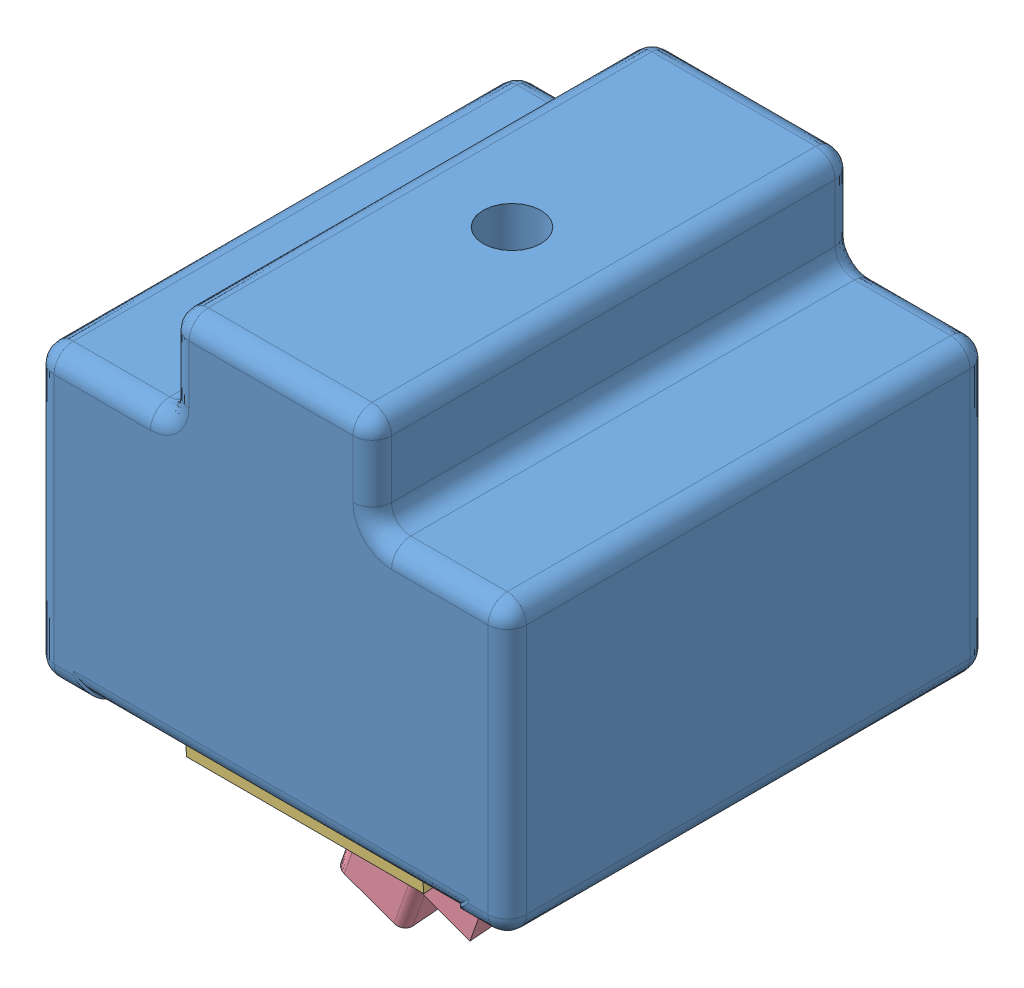
SolidWorks assembly Ankle Assembled, configuration Exploded. Lengths in mm.
Overall size (62.23 81.72 63.5).
6 component instances, 6 part files, 16 mates.
Components (placement in the parent):
- Ankle Exterior-1: Ankle Exterior [Default] at (-20.5538 13.3388 22.6611) size (62.23 50.8 63.5)
- Ankle Middle Joint Shell-1: Ankle Middle Joint Shell [Default] at (30.5162 13.8468 51.8711) x (-1 0 0) z (0 -0.084895 0.99639) size (40.89 25.02 50.04)
- Ankle Interior Joint-1: Ankle Interior Joint [Default] at (30.7702 13.8468 51.8711) x (-1 0 0) z (0 -0.084895 0.99639) size (45.97 24.51 48.01)
- Ankle Bottom Joint-1: Ankle Bottom Joint [Default] at (10.3232 12.5336 37.3643) x (0.924538 -0.379714 -0.032353) z (0 -0.084895 0.99639) size (27.55 36.83 34.71)
- Ankle Lock 1-1: Ankle Lock 1 [Default] at (39.1441 11.1758 53.3005) x (0 0.084895 -0.99639) z (1 0 0) size (22.86 14.73 2.03)
- Ankle Lock 2-1: Ankle Lock 2 [Default] at (12.5823 13.857 33.7997) x (1 0 0) z (0 -0.084895 0.99639) size (25.4 5.08 9.4)
Mates (geometry in assembly coordinates):
- Concentric1: concentric aligned: circle of Ankle Middle Joint Shell-1; circle of Ankle Interior Joint-1
- Coincident1: coincident aligned: plane of Ankle Middle Joint Shell-1 through (30.5162 13.8468 51.8711) normal (1 0 0); plane of Ankle Interior Joint-1 through (30.5162 13.8468 51.8711) normal (1 0 0)
- Coincident2: coincident anti-aligned: plane of Ankle Middle Joint Shell-1 through (30.5162 13.8468 51.8711) normal (0 -0.99639 -0.084895); plane of Ankle Interior Joint-1 through (30.7702 13.8468 51.8711) normal (0 0.99639 0.084895)
- Distance1: distance = 1 mm anti-aligned: plane of Ankle Interior Joint-1 through (30.5162 13.8468 51.8711) normal (1 0 0); plane of Ankle Exterior-1 through (31.5162 16.3868 26.4711) normal (-1 0 0)
- LimitAngle1: limit planar angle = 0.264068 rad aligned: plane of Ankle Middle Joint Shell-1 through (30.5162 13.8468 51.8711) normal (0 -0.99639 -0.084895); plane of Ankle Exterior-1 through (-20.5538 23.8372 24.4227) normal (0 -0.939693 -0.34202)
- Concentric4: concentric aligned: circle of Ankle Exterior-1; circle of Ankle Middle Joint Shell-1
- Concentric5: concentric anti-aligned: circle of Ankle Interior Joint-1; circle of Ankle Bottom Joint-1
- Distance2: distance = 0.5 mm anti-aligned: plane of Ankle Bottom Joint-1 through (10.3232 9.9568 67.6077) normal (0 -0.084895 0.99639); plane of Ankle Interior Joint-1 through (-3.0118 9.9143 68.1059) normal (0 0.084895 -0.99639)
- LimitAngle2: limit planar angle = 0.119066 rad anti-aligned: plane of Ankle Interior Joint-1 through (30.7702 11.3159 51.6555) normal (0 -0.99639 -0.084895); plane of Ankle Bottom Joint-1 through (-4.9405 10.7271 37.2103) normal (-0.118785 0.989336 0.084294)
- Concentric6: concentric aligned: circle of Ankle Interior Joint-1; circle of Ankle Lock 1-1
- Coincident4: coincident: plane of Ankle Interior Joint-1 through (30.7702 23.9701 52.7336) normal (0 -0.99639 -0.084895); line of Ankle Lock 1-1 through (25.4362 24.024 52.1009) axis (0 0.084895 -0.99639)
- Parallel1: parallel: line of Ankle Interior Joint-1 through (25.6902 12.2755 40.3933) axis (0 -0.084895 0.99639); plane of Ankle Lock 1-1 through (25.4362 22.989 64.2489) normal (1 0 0)
- Parallel2: parallel aligned: plane of Ankle Interior Joint-1 through (30.7702 16.3776 52.0867) normal (0 -0.99639 -0.084895); plane of Ankle Lock 2-1 through (12.5823 13.857 33.7997) normal (0 -0.99639 -0.084895)
- Coincident5: coincident: plane of Ankle Interior Joint-1 through (30.7702 16.3776 52.0867) normal (0 -0.99639 -0.084895); line of Ankle Lock 2-1 through (22.8962 17.9409 33.7382) axis (0 0.084895 -0.99639)
- Coincident7: coincident: line of Ankle Middle Joint Shell-1 through (30.5162 15.6042 31.2448) axis (-1 0 0); plane of Ankle Lock 2-1 through (-2.5038 18.135 31.4605) normal (0 0.084895 -0.99639)
- Distance3: distance = 7.62 mm aligned: plane of Ankle Middle Joint Shell-1 through (30.5162 13.8468 51.8711) normal (1 0 0); plane of Ankle Lock 2-1 through (22.8962 17.9409 33.7382) normal (1 0 0)
